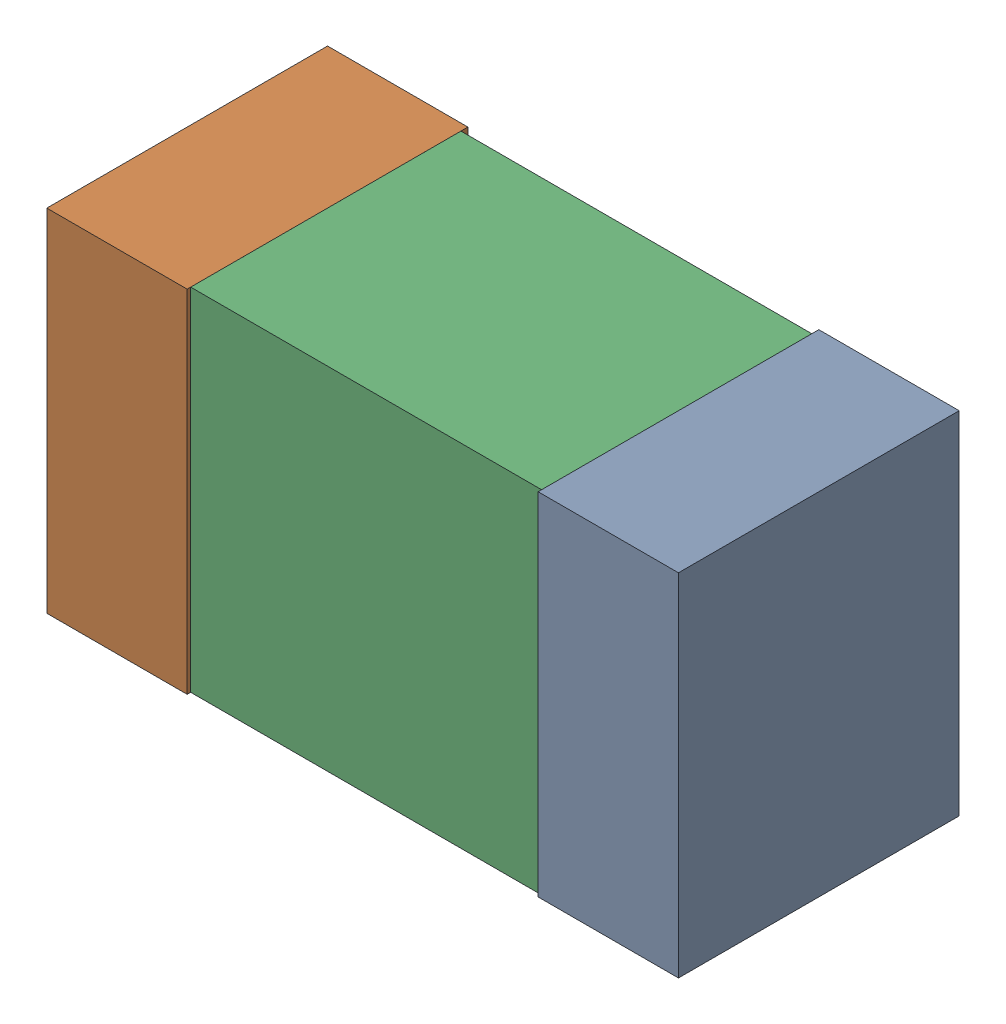
SolidWorks assembly L300_2PCB, configuration Default. Lengths in mm.
Overall size (1.8 1 0.8).
6 component instances, 2 part files, 0 mates.
Components (placement in the parent):
- 854785840-1: 854785840 [Default] at (134.5591 85.2909 -2.4638) size (0.4 1 0.8)
  - Extruded_4-1: Extruded_4 [Default] at origin size (0.4 1 0.8)
- 854785840-2: 854785840 [Default] at (133.1591 85.2909 -2.4638) size (0.4 1 0.8)
  - Extruded_4-1: Extruded_4 [Default] at origin size (0.4 1 0.8)
- 846483152-1: 846483152 [Default] at (133.8591 85.2909 -2.4438) size (1 1 0.77)
  - Extruded_3-1: Extruded_3 [Default] at origin size (1 1 0.77)
